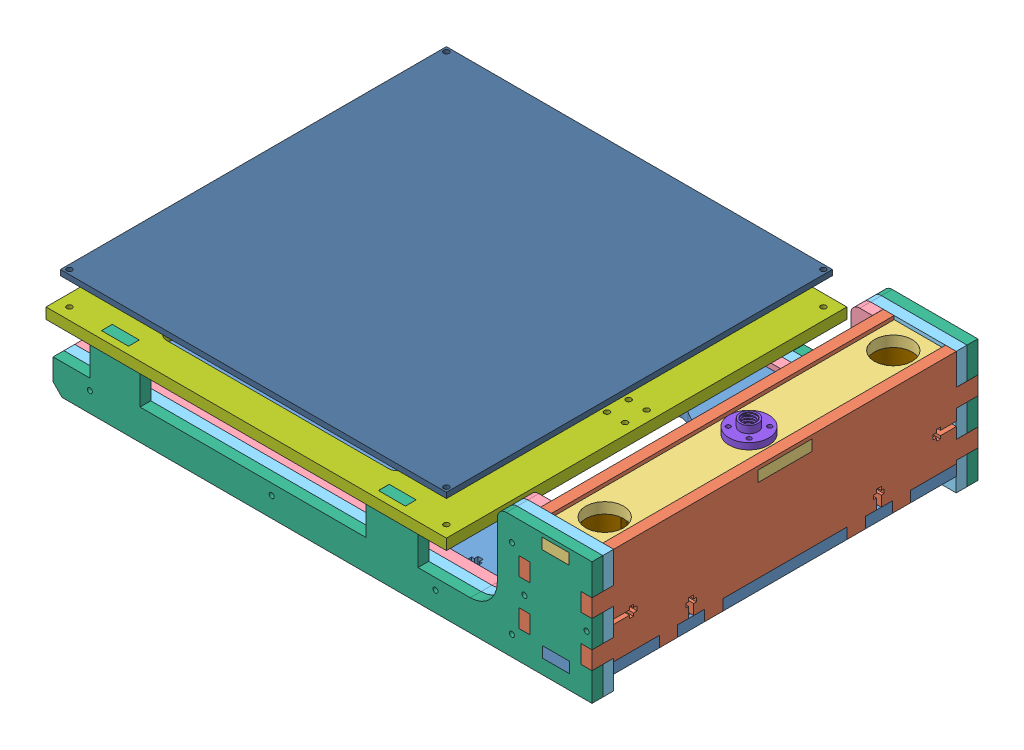
SolidWorks assembly Plywood_table_ver2, configuration По умолчанию. Lengths in mm.
Overall size (298.85 73.74 222).
15 component instances, 10 part files, 39 mates.
Components (placement in the parent):
- Part_A_ver2-1: Part_A_ver2 [По умолчанию] at (206.6203 226.753 241.4519) size (298.78 6 214)
- Part_C_ver2-1: Part_C_ver2 [Default] at (361.1245 255.753 241.8619) x (0 0 1) z (0 -1 0) size (214 6 60)
- Part_C_ver2-2: Part_C_ver2 [Default] at (320.656 255.753 241.8619) x (0 0 -1) z (0 -1 0) size (214 6 60)
- Part_D_ver2-1: Part_D_ver2 [Default] at (340.891 278.753 241.8619) x (0 0 1) z (-1 0 0) size (214 6 40.47)
- Part_E_ver2-1: Part_E_ver2 [Default] at (229.5286 229.753 330.8619) size (258.31 68 6)
- Part_E_ver2-2: Part_E_ver2 [Default] at (229.4571 229.753 146.8628) x (1 0 0.000007) z (-0.000007 0 1) size (258.31 68 6)
- Part_F_ver2-2: Part_F_ver2 [Default] at (211.6638 248.753 140.8627) x (1 0 0.000007) z (-0.000007 0 1) size (298.78 68 6)
- Part_F_ver2-3: Part_F_ver2 [Default] at (211.7353 248.753 336.8619) size (298.78 68 6)
- Part_G_ver2-1: Part_G_ver2 [Default] at (211.6638 248.753 134.8627) x (1 0 0.000007) z (-0.000007 0 1) size (298.78 68 6)
- Part_G_ver2-2: Part_G_ver2 [Default] at (211.7353 248.753 342.8619) size (298.78 68 6)
- Part_H_ver2-1: Part_H_ver2 [По умолчанию] at (165.1863 255.753 243.3293) size (222 6 222)
- 1187-B2P-A-1: 1187-B2P-A [По умолчанию] at (341.156 286.503 241.8619) x (-0.999985 0 0.005554) z (-0.005554 0 -0.999985) size (22 11.99 22)
- Plastic_part-1: Plastic_part [По умолчанию] at (340.891 232.753 166.8619) size (28.47 46 40)
- Plastic_part-2: Plastic_part [По умолчанию] at (340.891 278.753 316.8619) x (1 0 0) z (0 0 -1) size (28.47 46 40)
- HEATBED MK3-1: HEATBED MK3 [По умолчанию] at (173.4182 279.753 241.8618) size (214 3 214)
Mates (geometry in assembly coordinates):
- Совпадение4: coincident anti-aligned: plane of Part_A_ver2-1 through (206.6203 232.753 241.4519) normal (0 1 0); plane of Part_C_ver2-1 through (355.1245 232.753 207.3619) normal (0 -1 0)
- Совпадение5: coincident anti-aligned: plane of Part_A_ver2-1 through (355.1245 232.753 311.3619) normal (1 0 0); plane of Part_C_ver2-1 through (355.1245 255.753 241.8619) normal (-1 0 0)
- Совпадение6: coincident: plane of Part_A_ver2-1 through (355.1245 232.753 301.3619) normal (0 0 1); line of Part_C_ver2-1 through (361.1245 232.753 301.3619) axis (0 -1 0)
- Совпадение7: coincident anti-aligned: plane of Part_A_ver2-1 through (206.6203 232.753 241.4519) normal (0 1 0); plane of Part_C_ver2-2 through (326.656 232.753 276.3619) normal (0 -1 0)
- Совпадение8: coincident anti-aligned: plane of Part_A_ver2-1 through (320.656 232.753 311.3619) normal (0 0 -1); plane of Part_C_ver2-2 through (326.656 226.753 311.3619) normal (0 0 1)
- Совпадение9: coincident anti-aligned: plane of Part_A_ver2-1 through (326.656 232.753 311.3619) normal (-1 0 0); plane of Part_C_ver2-2 through (326.656 255.753 241.8619) normal (1 0 0)
- Концентричный1: concentric aligned: circle of Part_A_ver2-1; circle of Part_D_ver2-1
- Концентричный4: concentric aligned: circle of Part_A_ver2-1; circle of Part_D_ver2-1
- Совпадение15: coincident anti-aligned: plane of Part_C_ver2-2 through (320.656 255.753 241.8619) normal (-1 0 0); plane of Part_E_ver2-1 through (320.656 278.753 336.8619) normal (1 0 0)
- Совпадение16: coincident anti-aligned: plane of Part_A_ver2-1 through (267.9467 232.753 330.8619) normal (0 0 1); plane of Part_E_ver2-1 through (313.656 281.753 330.8619) normal (0 0 -1)
- Совпадение17: coincident anti-aligned: plane of Part_A_ver2-1 through (206.6203 232.753 241.4519) normal (0 1 0); plane of Part_E_ver2-1 through (267.946 232.753 336.8619) normal (0 -1 0)
- Совпадение18: coincident anti-aligned: plane of Part_A_ver2-1 through (206.6203 226.753 241.4519) normal (0 -1 0); plane of Part_E_ver2-2 through (76.2745 226.753 152.8618) normal (0 1 0)
- Совпадение22: coincident anti-aligned: plane of Part_A_ver2-1 through (89.1467 232.753 152.8619) normal (0.000007 0 -1); plane of Part_E_ver2-2 through (313.5845 281.753 152.8634) normal (-0.000007 0 1)
- Совпадение26: coincident anti-aligned: plane of Part_E_ver2-2 through (313.5845 281.753 146.8634) normal (0.000007 0 -1); plane of Part_F_ver2-2 through (313.5845 281.753 146.8634) normal (-0.000007 0 1)
- Совпадение31: coincident aligned: plane of Part_E_ver2-2 through (62.2745 235.753 152.8617) normal (-1 0 -0.000007); plane of Part_F_ver2-2 through (62.2745 223.753 146.8617) normal (-1 0 -0.000007)
- Совпадение32: coincident aligned: plane of Part_E_ver2-2 through (62.2745 235.753 152.8617) normal (0 1 0); plane of Part_F_ver2-2 through (293.5845 235.753 146.8632) normal (0 1 0)
- Совпадение33: coincident anti-aligned: plane of Part_E_ver2-1 through (313.656 281.753 336.8619) normal (0 0 1); plane of Part_F_ver2-3 through (313.656 281.753 336.8619) normal (0 0 -1)
- Совпадение34: coincident aligned: plane of Part_E_ver2-1 through (62.346 235.753 336.8619) normal (0 1 0); plane of Part_F_ver2-3 through (293.656 235.753 342.8619) normal (0 1 0)
- Совпадение35: coincident aligned: plane of Part_E_ver2-1 through (62.346 235.753 336.8619) normal (-1 0 0); plane of Part_F_ver2-3 through (62.346 223.753 342.8619) normal (-1 0 0)
- Совпадение36: coincident aligned: plane of Part_F_ver2-2 through (62.2745 223.753 146.8617) normal (-1 0 -0.000007); plane of Part_G_ver2-1 through (62.2746 223.753 140.8617) normal (-1 0 -0.000007)
- Совпадение39: coincident anti-aligned: plane of Part_F_ver2-2 through (313.5846 281.753 140.8634) normal (0.000007 0 -1); plane of Part_G_ver2-1 through (313.5846 281.753 140.8634) normal (-0.000007 0 1)
- Совпадение40: coincident anti-aligned: plane of Part_F_ver2-3 through (313.656 281.753 342.8619) normal (0 0 1); plane of Part_G_ver2-2 through (313.656 281.753 342.8619) normal (0 0 -1)
- Совпадение41: coincident aligned: plane of Part_F_ver2-3 through (62.346 223.753 342.8619) normal (-1 0 0); plane of Part_G_ver2-2 through (62.346 223.753 348.8619) normal (-1 0 0)
- Совпадение42: coincident aligned: plane of Part_F_ver2-3 through (293.656 235.753 342.8619) normal (0 1 0); plane of Part_G_ver2-2 through (82.7467 235.753 348.8619) normal (0 1 0)
- Совпадение45: coincident anti-aligned: plane of Part_G_ver2-2 through (313.656 281.753 348.8619) normal (0 0 1); plane of Part_H_ver2-1 through (89.1467 261.753 348.8619) normal (0 0 -1)
- Концентричный5: concentric anti-aligned: cylinder of Part_D_ver2-1 through (341.156 284.753 241.8619) axis (0 -1 0) radius 5; cylinder of 1187-B2P-A-1 through (341.156 292.253 241.8619) axis (0 1 0) radius 5
- Совпадение46: coincident anti-aligned: plane of Part_D_ver2-1 through (340.891 284.753 241.8619) normal (0 1 0); plane of 1187-B2P-A-1 through (341.1283 284.753 236.862) normal (0 -1 0)
- Совпадение47: coincident anti-aligned: plane of Part_C_ver2-2 through (326.656 255.753 241.8619) normal (1 0 0); plane of Plastic_part-1 through (326.656 278.753 146.8619) normal (-1 0 0)
- Концентричный7: concentric anti-aligned: circle of Part_D_ver2-1; circle of Plastic_part-1
- Совпадение52: coincident anti-aligned: plane of Part_A_ver2-1 through (206.6203 232.753 241.4519) normal (0 1 0); plane of Plastic_part-1 through (341.156 232.753 161.8619) normal (0 -1 0)
- Совпадение53: coincident anti-aligned: plane of Part_A_ver2-1 through (206.6203 232.753 241.4519) normal (0 1 0); plane of Plastic_part-2 through (341.156 232.753 321.8619) normal (0 -1 0)
- Совпадение54: coincident anti-aligned: plane of Part_F_ver2-3 through (313.656 281.753 336.8619) normal (0 0 -1); plane of Plastic_part-2 through (326.656 232.753 336.8619) normal (0 0 1)
- Совпадение55: coincident anti-aligned: plane of Part_C_ver2-2 through (326.656 255.753 241.8619) normal (1 0 0); plane of Plastic_part-2 through (326.656 232.753 336.8619) normal (-1 0 0)
- Совпадение56: coincident anti-aligned: plane of Part_C_ver2-1 through (355.1245 284.753 226.8619) normal (0 -1 0); plane of Part_D_ver2-1 through (340.891 284.753 241.8619) normal (0 1 0)
- Совпадение57: coincident anti-aligned: plane of Part_G_ver2-2 through (82.7467 255.753 348.8619) normal (0 1 0); plane of Part_H_ver2-1 through (165.1863 255.753 243.3293) normal (0 -1 0)
- Совпадение58: coincident anti-aligned: plane of Part_G_ver2-2 through (104.1467 261.753 348.8619) normal (1 0 0); plane of Part_H_ver2-1 through (104.1467 261.753 348.8619) normal (-1 0 0)
- Расстояние1: distance = 15 mm anti-aligned: plane of Part_H_ver2-1 through (165.1863 261.753 243.3293) normal (0 1 0); plane of HEATBED MK3-1 through (173.4182 276.753 241.8618) normal (0 -1 0)
- Концентричный10: concentric anti-aligned: circle of Part_H_ver2-1; circle of HEATBED MK3-1
- Параллельность1: parallel aligned: plane of Part_H_ver2-1 through (67.4182 261.753 130.8618) normal (0 0 -1); plane of HEATBED MK3-1 through (66.4182 279.753 134.8618) normal (0 0 -1)
